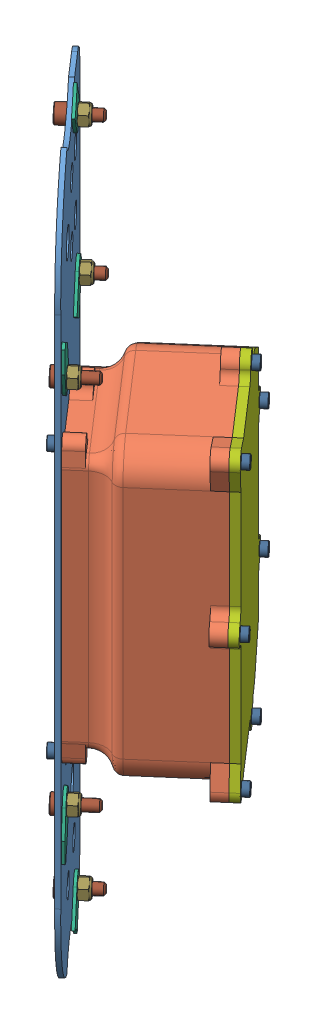
SolidWorks assembly EL-A0102-AA-Dashboard Assembly1, configuration Default. Lengths in mm.
Overall size (150 436.5 148.34).
102 component instances, 35 part files, 83 mates.
Components (placement in the parent):
- FR-40001-CF-Space Frame1-1: FR-40001-CF-Space Frame1 [Normal Chassis<As Machined>] at (-537.9548 -38.916 -519.6967) (suppressed, hidden)
- ST-A0200-AA-Inboard Steering1-1: ST-A0200-AA-Inboard Steering1 [Default] at (393.0306 -38.916 -479.6363) x (0 1 0) z (0 0 1) size (453.39 406.81 546.68) (suppressed, hidden)
  - ST-00020-AA-NARRco Rack MkII1-1: ST-00020-AA-NARRco Rack MkII1 [13t-Custom Length] at (0 -158.974 -60.8538) x (0 0 1) z (0 -1 0) size (60.02 415.44 50.74)
    - ST-00020-AA-NARRco Rack MkII Housing^ST-00020-AA-NARRco Rack MkII1-2: ST-00020-AA-NARRco Rack MkII Housing^ST-00020-AA-NARRco Rack MkII1 [17.4] at origin size (38.43 322.07 50.74) (virtual)
    - ST-00021-AA-NARRco Rack MkII Pinion^ST-00020-AA-NARRco Rack MkII1-1: ST-00021-AA-NARRco Rack MkII Pinion^ST-00020-AA-NARRco Rack MkII1 [Default] at (0 0 16.002) x (1 0 0) z (0 -1 0) size (58.43 56.52 31.98) (virtual)
    - ST-00022-AA-NARRco Rack MkII Rack^ST-00020-AA-NARRco Rack MkII1-1: ST-00022-AA-NARRco Rack MkII Rack^ST-00020-AA-NARRco Rack MkII1 [17.4] at origin size (15.88 404.88 15.88) (virtual)
    - ST-00023-AA-NARRco Rack MkII Bump Stop TT1119-01^ST-00020-AA-NARRco Rack MkII1-1: ST-00023-AA-NARRco Rack MkII Bump Stop TT1119-01^ST-00020-AA-NARRco Rack MkII1 [Default] at (0 194.818 0) x (-1 0 0) z (0 1 0) size (25.4 25.4 7.62) (virtual)
    - ST-00023-AA-NARRco Rack MkII Bump Stop TT1119-01^ST-00020-AA-NARRco Rack MkII1-2: ST-00023-AA-NARRco Rack MkII Bump Stop TT1119-01^ST-00020-AA-NARRco Rack MkII1 [Default] at (0 -194.818 0) x (1 0 0) z (0 -1 0) size (25.4 25.4 7.62) (virtual)
    - ST-10024-AA-Rack End Fastener^ST-00020-AA-NARRco Rack MkII1-1: ST-10024-AA-Rack End Fastener^ST-00020-AA-NARRco Rack MkII1 [Default] at (0 202.438 0) x (-0.837169 0 -0.546944) z (0 -1 0) size (12.7 12.7 31.32) (virtual)
    - ST-10024-AA-Rack End Fastener^ST-00020-AA-NARRco Rack MkII1-2: ST-10024-AA-Rack End Fastener^ST-00020-AA-NARRco Rack MkII1 [Default] at (0 -202.438 0) x (-0.837169 0 -0.546944) z (0 1 0) size (12.7 12.7 31.32) (virtual)
  - ST-00007-AA-SU Joint Borgeson1-1: ST-00007-AA-SU Joint Borgeson1 [Default] at (0 -174.976 36.3378) x (0 0.573576 0.819152) z (-1 0 0) size (87.37 64.05 41.39)
    - Clevis^ST-00007-AA-SU Joint Borgeson1-1: Clevis^ST-00007-AA-SU Joint Borgeson1 [Default] at (19.25 0 0) size (52.55 41.35 41.39) (virtual)
    - Clevis^ST-00007-AA-SU Joint Borgeson1-2: Clevis^ST-00007-AA-SU Joint Borgeson1 [Default] at (-15.7687 11.0413 0) x (-0.819152 0.573576 0) z (0.573576 0.819152 0) size (52.55 41.35 41.39) (virtual)
    - Joint^ST-00007-AA-SU Joint Borgeson1-1: Joint^ST-00007-AA-SU Joint Borgeson1 [Default] at origin size (15.41 40.1 40.1) (virtual)
  - ST-10008-AG-Lower Column1-1: ST-10008-AG-Lower Column1 [Single U-Joint] at (0 -176.646 33.9528) x (-0.165712 -0.807827 0.565646) z (0 0.573576 0.819152) size (30.03 24.96 239.93)
  - ST-00007-AB-SU Joint Borgeson1-1: ST-00007-AB-SU Joint Borgeson1 [Default] at (272.5838 -275.7567 2.1298) x (0 0.984808 -0.173648) z (0 0.173648 0.984808) size (106.79 41.39 97.86)
    - ST-00007-AA-SU Joint Borgeson1-1: ST-00007-AA-SU Joint Borgeson1 [Default] at (210.9791 272.5838 303.532) x (0.866025 0 0.5) z (0 1 0) size (87.37 64.05 41.39)
      - Clevis^ST-00007-AA-SU Joint Borgeson1-1: Clevis^ST-00007-AA-SU Joint Borgeson1 [Default] at (19.25 0 0) size (52.55 41.35 41.39) (virtual)
      - Clevis^ST-00007-AA-SU Joint Borgeson1-2: Clevis^ST-00007-AA-SU Joint Borgeson1 [Default] at (-15.7687 11.0413 0) x (-0.819152 0.573576 0) z (0.573576 0.819152 0) size (52.55 41.35 41.39) (virtual)
      - Joint^ST-00007-AA-SU Joint Borgeson1-1: Joint^ST-00007-AA-SU Joint Borgeson1 [Default] at origin size (15.41 40.1 40.1) (virtual)
  - ST-10004-AC-Upper Column1-1: ST-10004-AC-Upper Column1 [Default] at (0 -15.2751 264.4144) x (0 0.939693 0.34202) z (-0.909534 0.142154 -0.390564) size (101.6 19.05 19.05)
  - ST-10005-BB-Upper Support1-4: ST-10005-BB-Upper Support1 [Default] at (0 47.65 287.3172) x (-1 0 0) z (0 1 0) size (339.46 194.46 164.58)
  - ST-00006-AA-Upper Column Bearing (2938T23)1-1: ST-00006-AA-Upper Column Bearing (2938T23)1 [Default] at (0 23.7222 278.6082) x (0 0.939693 0.34202) z (-0.975708 -0.074928 0.205863) size (19.05 31.75 31.75)
  - ST-00006-AA-Upper Column Bearing (2938T23)1-2: ST-00006-AA-Upper Column Bearing (2938T23)1 [Default] at (0 71.5779 296.0263) x (0 -0.939693 -0.34202) z (0.727107 -0.234805 0.645121) size (19.05 31.75 31.75)
  - ST-00003-AA-Longacre Spud1-1: ST-00003-AA-Longacre Spud1 [Default] at (0 93.9543 304.1706) x (0 -0.939693 -0.34202) z (0.869392 -0.169 0.464323) size (53.97 27.38 27.32)
  - ST-#####-AA-MOMO MOD 121-1: ST-#####-AA-MOMO MOD 121 [Default] at (0 119.9927 313.6478) x (-0.999984 0.001925 -0.00529) z (0 0.939693 0.34202) size (250 198.03 35.56)
  - ST-00002-AA-Longacre Quick Disconnect_52-566051-1: ST-00002-AA-Longacre Quick Disconnect_52-566051 [Default] at (0 102.9646 307.4501) x (0 -0.939693 -0.34202) z (0.868826 0.16934 -0.465258) size (41.4 80.01 80.01)
  - ST-10009-AA-Lower Lower Column1-1: ST-10009-AA-Lower Lower Column1 [Single U-Joint] at (0 -174.976 -60.8538) x (0 1 0) z (0 0 1) size (30.03 24.96 55.78)
  - ST-10025-AA-Rack End Left1-1: ST-10025-AA-Rack End Left1 [Brute Forced Left] at (211.328 -158.974 -60.8538) x (0 0 -1) z (0 -1 0) size (25.4 30.73 21.27)
  - ST-10025-AA-Rack End1-1: ST-10025-AA-Rack End1 [Right] at (-211.328 -158.974 -60.8538) x (0 0 1) z (0 -1 0) size (25.4 30.73 21.27)
  - ST-00011-AB-Rack Mount Top1-1: ST-00011-AB-Rack Mount Top1 [Default] at (-155.4861 -158.974 -60.8538) x (0 1 0) z (0 0 1) size (59.69 11.13 15.88)
  - ST-00011-AB-Rack Mount Top1-2: ST-00011-AB-Rack Mount Top1 [Default] at (155.4861 -158.974 -60.8538) x (0 1 0) z (0 0 1) size (59.69 11.13 15.88)
  - ST-00012-AB-Rack Mount Bottom1-1: ST-00012-AB-Rack Mount Bottom1 [Default] at (-155.4861 -158.974 -60.8538) x (0 1 0) z (0 0 1) size (59.69 11.13 15.88)
  - ST-00012-AB-Rack Mount Bottom1-2: ST-00012-AB-Rack Mount Bottom1 [Default] at (155.4861 -158.974 -60.8538) x (0 1 0) z (0 0 1) size (59.69 11.13 15.88)
  - ST-70001-AB-Steering Rack Cover1-1: ST-70001-AB-Steering Rack Cover1 [Default] at (161.925 -244.8955 -31.75) x (-1 0 0) z (0 0 -1) size (388.4 152.4 55.88)
- EL-70040-AA-Dashboard Carbon Fiber Panel1-1: EL-70040-AA-Dashboard Carbon Fiber Panel1 [Default] at (408.7648 -38.916 -97.5804) x (0 1 0) z (0.656059 0 0.75471) size (431.8 2.54 114.47)
- EL-50041-AA-Dashboard Enclosure1-1: EL-50041-AA-Dashboard Enclosure1 [Default] at (434.2682 -38.916 -85.6643) x (0 1 0) z (-0.75471 0 0.656059) size (193.57 128.03 71.31)
- EL-80042-AA-Dashboard Display1-1: EL-80042-AA-Dashboard Display1 [Default] at (371.1883 85.036 -159.3307) x (0 -1 0) z (-0.75471 0 0.656059) size (132.58 114.23 10.91)
- EL-80043-AA-Dashboard PCB1-1: EL-80043-AA-Dashboard PCB1 [Default] at (483.1498 42.917 -55.7696) x (0 -1 0) z (0.75471 0 -0.656059) size (155.1 102.36 35.96)
- EL-80044-AA-Dashboard Controller Board1-1: EL-80044-AA-Dashboard Controller Board1 [Default] at (444.9269 -38.916 -86.7478) x (0 1 0) z (0.656059 0 0.75471) size (105.53 3.5 40.03)
- EL-30045-AA-Carbon Fiber Dash Panel Tabs1-1: EL-30045-AA-Carbon Fiber Dash Panel Tabs1 [Default] at (398.9627 -147.7409 -108.8565) x (0.525497 -0.598678 0.604515) z (0.75471 0 -0.656059) size (15.88 26.99 1.59)
- EL-30045-AA-Carbon Fiber Dash Panel Tabs1-2: EL-30045-AA-Carbon Fiber Dash Panel Tabs1 [Round Cutout] at (408.0839 -237.4011 -100.7835) x (0.5205 0.608735 0.598767) z (-0.75471 0 0.656059) size (15.88 26.76 1.59)
- EL-30045-AA-Carbon Fiber Dash Panel Tabs1-3: EL-30045-AA-Carbon Fiber Dash Panel Tabs1 [Middle Tabs] at (450.7883 -148.5331 -51.6576) x (0.603667 0.391586 0.69444) z (-0.75471 0 0.656059) size (15.88 33.34 1.59)
- EL-30045-AA-Carbon Fiber Dash Panel Tabs1-4: EL-30045-AA-Carbon Fiber Dash Panel Tabs1 [Default] at (400.1608 69.9089 -109.898) x (0.525497 0.598678 0.604515) z (-0.75471 0 0.656059) size (15.88 26.99 1.59)
- EL-30045-AA-Carbon Fiber Dash Panel Tabs1-5: EL-30045-AA-Carbon Fiber Dash Panel Tabs1 [Middle Tabs] at (449.5902 70.7011 -50.6161) x (0.603667 -0.391586 0.69444) z (0.75471 0 -0.656059) size (15.88 33.34 1.59)
- EL-30045-AA-Carbon Fiber Dash Panel Tabs1-6: EL-30045-AA-Carbon Fiber Dash Panel Tabs1 [Round Cutout] at (406.8858 159.5691 -99.742) x (0.5205 -0.608735 0.598767) z (0.75471 0 -0.656059) size (15.88 26.76 1.59)
- EL-60046-AA-Dashboard Enclosure Lid1-2: EL-60046-AA-Dashboard Enclosure Lid1 [Default] at (512.3994 -125.4743 -87.057) x (0.656059 0 0.75471) z (-0.75471 0 0.656059) size (128.03 193.57 4.76)
- EL-60047-AA-Dashboard Panel Clear Screen1-1: EL-60047-AA-Dashboard Panel Clear Screen1 [Default] at (431.2611 -38.916 -71.7014) x (0.75471 0 -0.656059) z (0 -1 0) size (1.59 66.67 114.3)
- AC-Heat Set Insert, M4x7-4.7 (94180A351)1-1: AC-Heat Set Insert, M4x7-4.7 (94180A351)1 [94180A351] at (393.689 -77.047 -118.5052) x (0.656059 0 0.75471) z (-0.75471 0 0.656059) size (6.35 6.35 4.7)
- AC-Heat Set Insert, M4x7-4.7 (94180A351)1-2: AC-Heat Set Insert, M4x7-4.7 (94180A351)1 [94180A351] at (423.6661 -117.916 -84.0204) x (0.544178 -0.558559 0.626005) z (-0.75471 0 0.656059) size (6.35 6.35 4.7)
- AC-Heat Set Insert, M4x7-4.7 (94180A351)1-3: AC-Heat Set Insert, M4x7-4.7 (94180A351)1 [94180A351] at (454.7239 -117.6987 -48.2925) x (0.544178 -0.558559 0.626005) z (-0.75471 0 0.656059) size (6.35 6.35 4.7)
- BR-Black Oxide C12.9 SHCS, M4x0.7-8 (91290A140)1-1: BR-Black Oxide C12.9 SHCS, M4x0.7-8 (91290A140)1 [91290A140] at (391.5079 -77.047 -116.6092) x (0.656059 0 0.75471) z (-0.75471 0 0.656059) size (7 7 12.17)
- BR-Black Oxide C12.9 SHCS, M4x0.7-8 (91290A140)1-2: BR-Black Oxide C12.9 SHCS, M4x0.7-8 (91290A140)1 [91290A140] at (421.485 -117.916 -82.1244) x (0.656059 0 0.75471) z (-0.75471 0 0.656059) size (7 7 12.17)
- BR-Black Oxide C12.9 SHCS, M4x0.7-8 (91290A140)1-3: BR-Black Oxide C12.9 SHCS, M4x0.7-8 (91290A140)1 [91290A140] at (452.5428 -117.6987 -46.3965) x (0.656059 0 0.75471) z (-0.75471 0 0.656059) size (7 7 12.17)
- FS-Black Oxide C12.9 SHCS, M6x1-16 (91290A321)1-1: FS-Black Oxide C12.9 SHCS, M6x1-16 (91290A321)1 [91290A321] at (453.6086 -148.5331 -54.1093) x (0.167998 -0.966658 0.19326) z (-0.75471 0 0.656059) size (10 10 22.29)
- EL-Steel Nylon Locknut, C8, M6x1-6 (90576A115)1-1: EL-Steel Nylon Locknut, C8, M6x1-6 (90576A115)1 [90576A115] at (453.0524 -148.5331 -53.6258) x (-0.656059 0 -0.75471) z (0.75471 0 -0.656059) size (10 11.55 6)
- FS-Black Oxide C12.9 SHCS, M6x1-16 (91290A321)1-2: FS-Black Oxide C12.9 SHCS, M6x1-16 (91290A321)1 [91290A321] at (400.8193 -147.7409 -110.4704) x (0.167998 -0.966658 0.19326) z (-0.75471 0 0.656059) size (10 10 22.29)
- FS-Black Oxide C12.9 SHCS, M6x1-16 (91290A321)1-3: FS-Black Oxide C12.9 SHCS, M6x1-16 (91290A321)1 [91290A321] at (408.7424 -237.4011 -101.3559) x (0.185994 -0.958972 0.213962) z (-0.75471 0 0.656059) size (10 10 22.29)
- EL-Steel Nylon Locknut, C8, M6x1-6 (90576A115)1-2: EL-Steel Nylon Locknut, C8, M6x1-6 (90576A115)1 [90576A115] at (410.348 -237.4011 -102.7516) x (-0.656059 0 -0.75471) z (0.75471 0 -0.656059) size (10 11.55 6)
- EL-Steel Nylon Locknut, C8, M6x1-6 (90576A115)1-3: EL-Steel Nylon Locknut, C8, M6x1-6 (90576A115)1 [90576A115] at (402.4249 -147.7409 -111.8661) x (-0.653043 -0.095776 -0.75124) z (0.75471 0 -0.656059) size (10 11.55 6)
- BR-Black Oxide C12.9 SHCS, M4x0.7-8 (91290A140)1-4: BR-Black Oxide C12.9 SHCS, M4x0.7-8 (91290A140)1 [91290A140] at (426.346 -100.006 -100.0441) x (0.387749 -0.806652 0.446054) z (-0.75471 0 0.656059) size (7 7 12.17)
- AC-Heat Set Insert, M4x7-4.7 (94180A351)1-4: AC-Heat Set Insert, M4x7-4.7 (94180A351)1 [94180A351] at (427.5158 -100.006 -101.061) x (0.544178 -0.558559 0.626005) z (-0.75471 0 0.656059) size (6.35 6.35 4.7)
- AC-Heat Set Insert, M4x7-4.7 (94180A351)1-5: AC-Heat Set Insert, M4x7-4.7 (94180A351)1 [94180A351] at (456.6776 -100.006 -67.5141) x (0.544178 -0.558559 0.626005) z (-0.75471 0 0.656059) size (6.35 6.35 4.7)
- BR-Black Oxide C12.9 SHCS, M4x0.7-8 (91290A140)1-5: BR-Black Oxide C12.9 SHCS, M4x0.7-8 (91290A140)1 [91290A140] at (455.5078 -100.006 -66.4972) x (0.646596 -0.169233 0.743824) z (-0.75471 0 0.656059) size (7 7 12.17)
- AC-Heat Set Insert, M2x0.4-2.9(94180A307)-1: AC-Heat Set Insert, M2x0.4-2.9(94180A307) [94180A307] at (431.5138 -89.166 -98.2757) x (-0.423191 0.764141 -0.486825) z (0.75471 0 -0.656059) size (3.58 3.58 2.92)
- AC-Heat Set Insert, M2x0.4-2.9(94180A307)-2: AC-Heat Set Insert, M2x0.4-2.9(94180A307) [94180A307] at (454.4758 -89.166 -71.8608) x (-0.423191 0.764141 -0.486825) z (0.75471 0 -0.656059) size (3.58 3.58 2.92)
- 90128A177_Zinc-Plated Alloy Steel Socket Head Screw, M2x0.4, 5mm1-1: 90128A177_Zinc-Plated Alloy Steel Socket Head Screw, M2x0.4, 5mm1 [90128A177] at (432.3141 -89.166 -98.9714) x (-0.618493 -0.333528 -0.711495) z (0.75471 0 -0.656059) size (3.8 3.8 7.09)
- 90128A177_Zinc-Plated Alloy Steel Socket Head Screw, M2x0.4, 5mm1-2: 90128A177_Zinc-Plated Alloy Steel Socket Head Screw, M2x0.4, 5mm1 [90128A177] at (455.2762 -89.166 -72.5566) x (0.466551 0.703049 0.536705) z (0.75471 0 -0.656059) size (3.8 3.8 7.09)
- AC-Heat Set Insert, M4x7-4.7 (94180A351)1-6: AC-Heat Set Insert, M4x7-4.7 (94180A351)1 [94180A351] at (473.7243 -129.6987 -127.9655) x (0.032788 0.99875 0.037718) z (0.75471 0 -0.656059) size (6.35 6.35 4.7)
- BR-Black Oxide C12.9 SHCS, M4x0.7-8 (91290A140)1-6: BR-Black Oxide C12.9 SHCS, M4x0.7-8 (91290A140)1 [91290A140] at (518.6227 -122.8067 -84.1086) x (0.649068 -0.145601 0.746667) z (0.75471 0 -0.656059) size (7 7 12.17)
- AC-Heat Set Insert, M4x7-4.7 (94180A351)1-7: AC-Heat Set Insert, M4x7-4.7 (94180A351)1 [94180A351] at (442.8335 -76.9989 -163.5013) x (-0.331829 0.862655 -0.381726) z (0.75471 0 -0.656059) size (6.35 6.35 4.7)
- AC-Heat Set Insert, M4x7-4.7 (94180A351)1-8: AC-Heat Set Insert, M4x7-4.7 (94180A351)1 [94180A351] at (514.7643 -122.8067 -80.7545) x (-0.582666 0.459592 -0.67028) z (0.75471 0 -0.656059) size (6.35 6.35 4.7)
- AC-Heat Set Insert, M4x7-4.7 (94180A351)1-9: AC-Heat Set Insert, M4x7-4.7 (94180A351)1 [94180A351] at (518.9578 -38.916 -75.9303) x (-0.363579 0.832393 -0.418249) z (0.75471 0 -0.656059) size (6.35 6.35 4.7)
- BR-Black Oxide C12.9 SHCS, M4x0.7-8 (91290A140)1-7: BR-Black Oxide C12.9 SHCS, M4x0.7-8 (91290A140)1 [91290A140] at (477.5828 -129.6987 -131.3196) x (0.573981 -0.484318 0.660289) z (0.75471 0 -0.656059) size (7 7 12.17)
- BR-Black Oxide C12.9 SHCS, M4x0.7-8 (91290A140)1-8: BR-Black Oxide C12.9 SHCS, M4x0.7-8 (91290A140)1 [91290A140] at (446.692 -76.9989 -166.8554) x (0.573981 -0.484318 0.660289) z (0.75471 0 -0.656059) size (7 7 12.17)
- BR-Black Oxide C12.9 SHCS, M4x0.7-8 (91290A140)1-9: BR-Black Oxide C12.9 SHCS, M4x0.7-8 (91290A140)1 [91290A140] at (522.8163 -38.916 -79.2844) x (0.649068 -0.145601 0.746667) z (0.75471 0 -0.656059) size (7 7 12.17)
- AC-Heat Set Insert, M4x7-4.7 (94180A351)1-10: AC-Heat Set Insert, M4x7-4.7 (94180A351)1 [94180A351] at (393.689 -0.785 -118.5052) x (0.656059 0 0.75471) z (0.75471 0 -0.656059) size (6.35 6.35 4.7)
- BR-Black Oxide C12.9 SHCS, M4x0.7-8 (91290A140)1-10: BR-Black Oxide C12.9 SHCS, M4x0.7-8 (91290A140)1 [91290A140] at (391.5079 -0.785 -116.6092) x (-0.656059 0 -0.75471) z (-0.75471 0 0.656059) size (7 7 12.17)
- AC-Heat Set Insert, M4x7-4.7 (94180A351)1-11: AC-Heat Set Insert, M4x7-4.7 (94180A351)1 [94180A351] at (423.6661 40.084 -84.0204) x (0.544178 0.558559 0.626005) z (-0.75471 0 0.656059) size (6.35 6.35 4.7)
- BR-Black Oxide C12.9 SHCS, M4x0.7-8 (91290A140)1-11: BR-Black Oxide C12.9 SHCS, M4x0.7-8 (91290A140)1 [91290A140] at (421.485 40.084 -82.1244) x (-0.656059 0 -0.75471) z (-0.75471 0 0.656059) size (7 7 12.17)
- AC-Heat Set Insert, M4x7-4.7 (94180A351)1-12: AC-Heat Set Insert, M4x7-4.7 (94180A351)1 [94180A351] at (454.7239 39.8667 -48.2925) x (0.544178 0.558559 0.626005) z (-0.75471 0 0.656059) size (6.35 6.35 4.7)
- BR-Black Oxide C12.9 SHCS, M4x0.7-8 (91290A140)1-12: BR-Black Oxide C12.9 SHCS, M4x0.7-8 (91290A140)1 [91290A140] at (452.5428 39.8667 -46.3965) x (-0.656059 0 -0.75471) z (-0.75471 0 0.656059) size (7 7 12.17)
- AC-Heat Set Insert, M4x7-4.7 (94180A351)1-13: AC-Heat Set Insert, M4x7-4.7 (94180A351)1 [94180A351] at (456.6776 22.174 -67.5141) x (0.544178 0.558559 0.626005) z (-0.75471 0 0.656059) size (6.35 6.35 4.7)
- BR-Black Oxide C12.9 SHCS, M4x0.7-8 (91290A140)1-13: BR-Black Oxide C12.9 SHCS, M4x0.7-8 (91290A140)1 [91290A140] at (455.5078 22.174 -66.4972) x (-0.646596 -0.169233 -0.743824) z (-0.75471 0 0.656059) size (7 7 12.17)
- BR-Black Oxide C12.9 SHCS, M4x0.7-8 (91290A140)1-14: BR-Black Oxide C12.9 SHCS, M4x0.7-8 (91290A140)1 [91290A140] at (426.346 22.174 -100.0441) x (-0.387749 -0.806652 -0.446054) z (-0.75471 0 0.656059) size (7 7 12.17)
- AC-Heat Set Insert, M4x7-4.7 (94180A351)1-14: AC-Heat Set Insert, M4x7-4.7 (94180A351)1 [94180A351] at (427.5158 22.174 -101.061) x (0.544178 0.558559 0.626005) z (-0.75471 0 0.656059) size (6.35 6.35 4.7)
- 90128A177_Zinc-Plated Alloy Steel Socket Head Screw, M2x0.4, 5mm1-3: 90128A177_Zinc-Plated Alloy Steel Socket Head Screw, M2x0.4, 5mm1 [90128A177] at (432.3141 11.334 -98.9714) x (0.618493 -0.333528 0.711495) z (0.75471 0 -0.656059) size (3.8 3.8 7.09)
- 90128A177_Zinc-Plated Alloy Steel Socket Head Screw, M2x0.4, 5mm1-4: 90128A177_Zinc-Plated Alloy Steel Socket Head Screw, M2x0.4, 5mm1 [90128A177] at (455.2762 11.334 -72.5566) x (-0.466551 0.703049 -0.536705) z (0.75471 0 -0.656059) size (3.8 3.8 7.09)
- FS-Black Oxide C12.9 SHCS, M6x1-16 (91290A321)1-4: FS-Black Oxide C12.9 SHCS, M6x1-16 (91290A321)1 [91290A321] at (453.6086 70.7011 -54.1093) x (-0.167998 -0.966658 -0.19326) z (-0.75471 0 0.656059) size (10 10 22.29)
- EL-Steel Nylon Locknut, C8, M6x1-6 (90576A115)1-4: EL-Steel Nylon Locknut, C8, M6x1-6 (90576A115)1 [90576A115] at (453.0524 70.7011 -53.6258) x (-0.656059 0 -0.75471) z (0.75471 0 -0.656059) size (10 11.55 6)
- EL-Steel Nylon Locknut, C8, M6x1-6 (90576A115)1-5: EL-Steel Nylon Locknut, C8, M6x1-6 (90576A115)1 [90576A115] at (402.4249 69.9089 -111.8661) x (-0.653043 0.095776 -0.75124) z (0.75471 0 -0.656059) size (10 11.55 6)
- FS-Black Oxide C12.9 SHCS, M6x1-16 (91290A321)1-5: FS-Black Oxide C12.9 SHCS, M6x1-16 (91290A321)1 [91290A321] at (400.8193 69.9089 -110.4704) x (-0.167998 -0.966658 -0.19326) z (-0.75471 0 0.656059) size (10 10 22.29)
- FS-Black Oxide C12.9 SHCS, M6x1-16 (91290A321)1-6: FS-Black Oxide C12.9 SHCS, M6x1-16 (91290A321)1 [91290A321] at (408.7424 159.5691 -101.3559) x (-0.185994 -0.958972 -0.213962) z (-0.75471 0 0.656059) size (10 10 22.29)
- EL-Steel Nylon Locknut, C8, M6x1-6 (90576A115)1-6: EL-Steel Nylon Locknut, C8, M6x1-6 (90576A115)1 [90576A115] at (410.348 159.5691 -102.7516) x (-0.656059 0 -0.75471) z (0.75471 0 -0.656059) size (10 11.55 6)
- AC-Heat Set Insert, M4x7-4.7 (94180A351)1-15: AC-Heat Set Insert, M4x7-4.7 (94180A351)1 [94180A351] at (514.7643 44.9747 -80.7545) x (0.582666 0.459592 0.67028) z (0.75471 0 -0.656059) size (6.35 6.35 4.7)
- BR-Black Oxide C12.9 SHCS, M4x0.7-8 (91290A140)1-15: BR-Black Oxide C12.9 SHCS, M4x0.7-8 (91290A140)1 [91290A140] at (518.6227 44.9747 -84.1086) x (-0.649068 -0.145601 -0.746667) z (0.75471 0 -0.656059) size (7 7 12.17)
- BR-Black Oxide C12.9 SHCS, M4x0.7-8 (91290A140)1-16: BR-Black Oxide C12.9 SHCS, M4x0.7-8 (91290A140)1 [91290A140] at (477.5828 51.8667 -131.3196) x (-0.573981 -0.484318 -0.660289) z (0.75471 0 -0.656059) size (7 7 12.17)
- AC-Heat Set Insert, M4x7-4.7 (94180A351)1-16: AC-Heat Set Insert, M4x7-4.7 (94180A351)1 [94180A351] at (473.7243 51.8667 -127.9655) x (-0.032788 0.99875 -0.037718) z (0.75471 0 -0.656059) size (6.35 6.35 4.7)
- AC-Heat Set Insert, M4x7-4.7 (94180A351)1-17: AC-Heat Set Insert, M4x7-4.7 (94180A351)1 [94180A351] at (442.8335 -0.8331 -163.5013) x (0.331829 0.862655 0.381726) z (0.75471 0 -0.656059) size (6.35 6.35 4.7)
- BR-Black Oxide C12.9 SHCS, M4x0.7-8 (91290A140)1-17: BR-Black Oxide C12.9 SHCS, M4x0.7-8 (91290A140)1 [91290A140] at (446.692 -0.8331 -166.8554) x (-0.573981 -0.484318 -0.660289) z (0.75471 0 -0.656059) size (7 7 12.17)
- AC-Heat Set Insert, M2x0.4-2.9(94180A307)-3: AC-Heat Set Insert, M2x0.4-2.9(94180A307) [94180A307] at (454.4758 11.334 -71.8608) x (0.423191 0.764141 0.486825) z (0.75471 0 -0.656059) size (3.58 3.58 2.92)
- AC-Heat Set Insert, M2x0.4-2.9(94180A307)-4: AC-Heat Set Insert, M2x0.4-2.9(94180A307) [94180A307] at (431.5138 11.334 -98.2757) x (0.423191 0.764141 0.486825) z (0.75471 0 -0.656059) size (3.58 3.58 2.92)
Mates (geometry in assembly coordinates):
- Coincident5: coincident: cylinder of ST-A0200-AA-Inboard Steering1-1/ST-10005-BB-Upper Support1-4; unknown of FR-40001-CF-Space Frame1-1
- Parallel2: parallel aligned: plane of ST-A0200-AA-Inboard Steering-1 through (393.0306 -38.916 -479.6363) normal (0 1 0)
- Parallel4: parallel aligned: plane of ST-A0200-AA-Inboard Steering-1 through (393.0306 -38.916 -479.6363) normal (0 0 1)
- Tangent2: tangent anti-aligned: cylinder of ST-A0200-AA-Inboard Steering-1/ST-10005-BB-Upper Support-4 through (339.0305 -43.996 -192.319) axis (0.537412 -0.573576 0.618222) radius 9.525; plane of Carbon Fiber Dashboard Panel-1 through (421.3036 117.9839 -83.1562) normal (0.75471 0 -0.656059)
- Tangent3: tangent anti-aligned: cylinder of ST-A0200-AA-Inboard Steering-1/ST-10005-BB-Upper Support-4 through (468.7081 104.568 -43.1421) axis (-0.537412 -0.573576 -0.618222) radius 9.525; plane of Carbon Fiber Dashboard Panel-1 through (421.3036 117.9839 -83.1562) normal (0.75471 0 -0.656059)
- Coincident10: coincident aligned: plane of FR-40001-CF-Space Frame-1 through (-537.9548 -38.916 -519.6967) normal (0 1 0); plane of EL-70040-AA-Dashboard Carbon Fiber Panel-1 through (408.7648 -38.916 -97.5804) normal (0 1 0)
- Tangent5: tangent anti-aligned: torus of ST-A0200-AA-Inboard Steering-1/ST-10005-BB-Upper Support-4; plane of Carbon Fiber Dashboard Panel-1 through (458.0942 113.484 -36.9618) normal (0.656059 0 0.75471)
- Coincident11: coincident anti-aligned: plane of Carbon Fiber Dashboard Panel-1 through (421.3036 117.9839 -83.1562) normal (0.75471 0 -0.656059); plane of BA-Dashboard Enclosure-1 through (425.6419 -38.916 -78.1655) normal (-0.75471 0 0.656059)
- Coincident14: coincident aligned: plane of FR-40001-CF-Space Frame-1 through (-537.9548 -38.916 -519.6967) normal (0 1 0); plane of BA-Dashboard Enclosure-1 through (434.2682 -38.916 -85.6643) normal (0 1 0)
- Distance1: distance = 3.175 mm anti-aligned: plane of Dashboard Display-1 through (455.0146 -93.776 -49.2156) normal (-0.75471 0 0.656059); plane of Carbon Fiber Dashboard Panel-1 through (421.3036 117.9839 -83.1562) normal (0.75471 0 -0.656059)
- Width1: width anti-aligned: plane of Carbon Fiber Dashboard Panel-1 through (451.2577 15.059 -48.6979) normal (0 -1 0); plane of Carbon Fiber Dashboard Panel-1 through (451.2577 -92.891 -48.6979) normal (0 1 0); plane of Dashboard Display-1 through (422.4619 27.374 -103.2928) normal (0 1 0); plane of Dashboard Display-1 through (422.4619 -105.206 -103.2928) normal (0 -1 0)
- Distance2: distance = 4.7625 mm aligned: plane of BA-Dashboard Enclosure-1 through (456.8867 -38.916 -42.2225) normal (0.656059 0 0.75471); plane of Carbon Fiber Dashboard Panel-1 through (458.0942 113.484 -36.9618) normal (0.656059 0 0.75471)
- Distance3: distance = 1.5 mm anti-aligned: plane of Dashboard Display-1 through (457.2449 -38.916 -51.1465) normal (0.656059 0 0.75471); plane of BA-Dashboard Enclosure-1 through (453.6064 -38.916 -45.996) normal (-0.656059 0 -0.75471)
- Distance4: distance = 8 mm anti-aligned: plane of NHD-4.3-480272MF-34-Controller-Board-1 through (444.8514 -38.916 -86.6822) normal (0.75471 0 -0.656059); plane of Dashboard PCB-1 through (448.7235 -39.6458 -94.4219) normal (-0.75471 0 0.656059)
- Concentric1: concentric aligned: cylinder of Dashboard Display-1 through (452.1133 -81.416 -63.5464) axis (0.75471 0 -0.656059) radius 1.2245; circle of Dashboard PCB-1
- Parallel6: parallel anti-aligned: plane of BA-Dashboard Enclosure-1 through (453.6064 -38.916 -45.996) normal (-0.656059 0 -0.75471); plane of Dashboard PCB-1 through (472.9084 -115.846 -66.6003) normal (0.656059 0 0.75471)
- Distance5: distance = 5 mm anti-aligned: plane of NHD-4.3-480272MF-34-Controller-Board-1 through (444.0967 -38.916 -86.0261) normal (-0.75471 0 0.656059); plane of Dashboard Display-1 through (422.4619 -103.206 -103.2928) normal (0.75471 0 -0.656059)
- Symmetric1: symmetric aligned: plane of Dashboard Display-1 through (411.3864 -38.916 -103.9007) normal (-0.656059 0 -0.75471); plane of NHD-4.3-480272MF-34-Controller-Board-1 through (457.2449 -38.916 -51.1465) normal (0.656059 0 0.75471); plane of Dashboard Display-1 through (444.9269 -38.916 -86.7478) normal (0.656059 0 0.75471)
- Coincident18: coincident aligned: plane of BA-Dashboard Enclosure-1 through (434.2682 -38.916 -85.6643) normal (0 1 0); plane of NHD-4.3-480272MF-34-Controller-Board-1 through (444.9269 -38.916 -86.7478) normal (0 1 0)
- Coincident19: coincident anti-aligned: plane of BA-Dashboard Enclosure-1 through (442.4153 -38.916 -92.7465) normal (0.75471 0 -0.656059); plane of Dashboard Enclosure Lid-1
- Coincident20: coincident anti-aligned: plane of BA-Dashboard Enclosure-1 through (425.6419 -113.916 -78.1655) normal (0 -1 0); plane of Dashboard Enclosure Lid-1 through (505.9428 -118.291 -84.8663) normal (0 1 0)
- Coincident21: coincident aligned: plane of BA-Dashboard Enclosure-1 through (456.8867 -38.916 -42.2225) normal (0.656059 0 0.75471); plane of Dashboard Enclosure Lid-1 through (505.9428 -118.291 -84.8663) normal (0.656059 0 0.75471)
- Coincident22: coincident anti-aligned: plane of Carbon Fiber Dashboard Panel-1 through (421.3036 117.9839 -83.1562) normal (0.75471 0 -0.656059); plane of EL-30045-AA-Carbon Fiber Dash Panel Tabs-1 through (398.9627 -147.7409 -108.8565) normal (-0.75471 0 0.656059)
- Coincident231: coincident anti-aligned: plane of Carbon Fiber Dashboard Panel-1 through (421.3036 117.9839 -83.1562) normal (0.75471 0 -0.656059); plane of EL-30045-AA-Carbon Fiber Dash Panel Tabs-2 through (406.8858 -237.4011 -99.742) normal (-0.75471 0 0.656059)
- Coincident241: coincident anti-aligned: plane of Carbon Fiber Dashboard Panel-1 through (421.3036 117.9839 -83.1562) normal (0.75471 0 -0.656059); plane of EL-30045-AA-Carbon Fiber Dash Panel Tabs-3 through (449.5902 -148.5331 -50.6161) normal (-0.75471 0 0.656059)
- Coincident242: coincident anti-aligned: plane of BA-Dashboard Enclosure-1 through (479.4602 -38.916 -124.9491) normal (0.75471 0 -0.656059); plane of Dashboard Enclosure Lid-2
- Concentric2: concentric aligned: cylinder of BA-Dashboard Enclosure-1 through (397.9531 -77.047 -122.2119) axis (-0.75471 0 0.656059) radius 3.025; cylinder of AC-Heat Set Insert, M4x7-4.7 (94180A351)-1 through (391.9154 -77.047 -116.9634) axis (-0.75471 0 0.656059) radius 2
- Coincident243: coincident aligned: plane of BA-Dashboard Enclosure-1 through (425.6419 -38.916 -78.1655) normal (-0.75471 0 0.656059); plane of AC-Heat Set Insert, M4x7-4.7 (94180A351)-1 through (391.9154 -75.047 -116.9634) normal (-0.75471 0 0.656059)
- Concentric31: concentric aligned: cylinder of BA-Dashboard Enclosure-1 through (427.9302 -117.916 -87.7272) axis (-0.75471 0 0.656059) radius 3.025; cylinder of AC-Heat Set Insert, M4x7-4.7 (94180A351)-2 through (421.8925 -117.916 -82.4787) axis (-0.75471 0 0.656059) radius 2
- Coincident244: coincident aligned: plane of BA-Dashboard Enclosure-1 through (425.6419 -38.916 -78.1655) normal (-0.75471 0 0.656059); plane of AC-Heat Set Insert, M4x7-4.7 (94180A351)-2 through (422.6254 -116.2571 -81.6356) normal (-0.75471 0 0.656059)
- Concentric41: concentric aligned: cylinder of BA-Dashboard Enclosure-1 through (458.988 -117.6987 -51.9992) axis (-0.75471 0 0.656059) radius 3.025; cylinder of AC-Heat Set Insert, M4x7-4.7 (94180A351)-3 through (452.9503 -117.6987 -46.7508) axis (-0.75471 0 0.656059) radius 2
- Coincident245: coincident aligned: plane of BA-Dashboard Enclosure-1 through (425.6419 -38.916 -78.1655) normal (-0.75471 0 0.656059); plane of AC-Heat Set Insert, M4x7-4.7 (94180A351)-3 through (453.6832 -116.0398 -45.9077) normal (-0.75471 0 0.656059)
- Concentric5: concentric anti-aligned: cylinder of AC-Heat Set Insert, M4x7-4.7 (94180A351)-1 through (391.9154 -77.047 -116.9634) axis (-0.75471 0 0.656059) radius 2; cylinder of BR-Black Oxide C12.9 SHCS, M4x0.7-8 (91290A140)-1 through (396.0361 -77.047 -120.5455) axis (0.75471 0 -0.656059) radius 2
- Coincident246: coincident: line of Carbon Fiber Dashboard Panel-1 through (383.1067 164.284 -123.2251) axis (0 -1 0); plane of BR-Black Oxide C12.9 SHCS, M4x0.7-8 (91290A140)-1 through (389.9984 -73.747 -115.297) normal (0.75471 0 -0.656059)
- Concentric6: concentric anti-aligned: cylinder of AC-Heat Set Insert, M4x7-4.7 (94180A351)-2 through (421.8925 -117.916 -82.4787) axis (-0.75471 0 0.656059) radius 2; cylinder of BR-Black Oxide C12.9 SHCS, M4x0.7-8 (91290A140)-2 through (426.0132 -117.916 -86.0608) axis (0.75471 0 -0.656059) radius 2
- Coincident247: coincident anti-aligned: plane of Carbon Fiber Dashboard Panel-1 through (419.3866 117.9839 -81.4898) normal (-0.75471 0 0.656059); plane of BR-Black Oxide C12.9 SHCS, M4x0.7-8 (91290A140)-2 through (419.9755 -114.616 -80.8123) normal (0.75471 0 -0.656059)
- Concentric7: concentric anti-aligned: cylinder of AC-Heat Set Insert, M4x7-4.7 (94180A351)-3 through (452.9503 -117.6987 -46.7508) axis (-0.75471 0 0.656059) radius 2; cylinder of BR-Black Oxide C12.9 SHCS, M4x0.7-8 (91290A140)-3 through (457.0711 -117.6987 -50.3328) axis (0.75471 0 -0.656059) radius 2
- Coincident248: coincident anti-aligned: plane of Carbon Fiber Dashboard Panel-1 through (419.3866 117.9839 -81.4898) normal (-0.75471 0 0.656059); plane of BR-Black Oxide C12.9 SHCS, M4x0.7-8 (91290A140)-3 through (451.0334 -114.3987 -45.0844) normal (0.75471 0 -0.656059)
- Concentric9: concentric anti-aligned: cylinder of FS-Black Oxide C12.9 SHCS, M6x1-16 (91290A321)-1 through (461.9104 -148.5331 -61.3259) axis (0.75471 0 -0.656059) radius 3; cylinder of EL-Steel Nylon Locknut, C8, M6x1-6 (90576A115)-1 through (455.3166 -148.5331 -55.594) axis (-0.75471 0 0.656059) radius 3
- Coincident249: coincident anti-aligned: plane of EL-30045-AA-Carbon Fiber Dash Panel Tabs-3 through (450.7883 -148.5331 -51.6576) normal (0.75471 0 -0.656059); plane of EL-Steel Nylon Locknut, C8, M6x1-6 (90576A115)-1 through (450.7883 -148.5331 -51.6576) normal (-0.75471 0 0.656059)
- Concentric10: concentric aligned: cylinder of EL-30045-AA-Carbon Fiber Dash Panel Tabs-1 through (400.1608 -147.7409 -109.898) axis (0.75471 0 -0.656059) radius 3.3; cylinder of FS-Black Oxide C12.9 SHCS, M6x1-16 (91290A321)-2 through (409.1211 -147.7409 -117.687) axis (0.75471 0 -0.656059) radius 3
- Coincident250: coincident anti-aligned: plane of Carbon Fiber Dashboard Panel-1 through (419.3866 117.9839 -81.4898) normal (-0.75471 0 0.656059); plane of FS-Black Oxide C12.9 SHCS, M6x1-16 (91290A321)-2 through (400.0264 -146.5373 -103.7612) normal (0.75471 0 -0.656059)
- Concentric11: concentric anti-aligned: circle of Carbon Fiber Dash Panel Tabs-2; cylinder of FS-Black Oxide C12.9 SHCS, M6x1-16 (91290A321)-3 through (417.0442 -237.4011 -108.5725) axis (0.75471 0 -0.656059) radius 3
- Coincident251: coincident anti-aligned: plane of Carbon Fiber Dashboard Panel-1 through (419.3866 117.9839 -81.4898) normal (-0.75471 0 0.656059); plane of FS-Black Oxide C12.9 SHCS, M6x1-16 (91290A321)-3 through (407.9258 -236.0687 -94.674) normal (0.75471 0 -0.656059)
- Concentric12: concentric anti-aligned: cylinder of FS-Black Oxide C12.9 SHCS, M6x1-16 (91290A321)-3 through (417.0442 -237.4011 -108.5725) axis (0.75471 0 -0.656059) radius 3; cylinder of EL-Steel Nylon Locknut, C8, M6x1-6 (90576A115)-2 through (412.6121 -237.4011 -104.7198) axis (-0.75471 0 0.656059) radius 3
- Coincident252: coincident anti-aligned: plane of EL-30045-AA-Carbon Fiber Dash Panel Tabs-2 through (408.0839 -237.4011 -100.7835) normal (0.75471 0 -0.656059); plane of EL-Steel Nylon Locknut, C8, M6x1-6 (90576A115)-2 through (408.0839 -237.4011 -100.7835) normal (-0.75471 0 0.656059)
- Concentric13: concentric anti-aligned: cylinder of FS-Black Oxide C12.9 SHCS, M6x1-16 (91290A321)-2 through (409.1211 -147.7409 -117.687) axis (0.75471 0 -0.656059) radius 3; cylinder of EL-Steel Nylon Locknut, C8, M6x1-6 (90576A115)-3 through (400.1608 -147.7409 -109.898) axis (-0.75471 0 0.656059) radius 2.3505
- Coincident253: coincident anti-aligned: plane of EL-30045-AA-Carbon Fiber Dash Panel Tabs-1 through (400.1608 -147.7409 -109.898) normal (0.75471 0 -0.656059); plane of EL-Steel Nylon Locknut, C8, M6x1-6 (90576A115)-3 through (400.1608 -147.7409 -109.898) normal (-0.75471 0 0.656059)
- Concentric14: concentric aligned: cylinder of BA-Dashboard Enclosure-1 through (429.5158 -100.006 -102.7995) axis (-0.75471 0 0.656059) radius 3.025; cylinder of AC-Heat Set Insert, M4x7-4.7 (94180A351)-4 through (425.7422 -100.006 -99.5192) axis (-0.75471 0 0.656059) radius 2
- Coincident254: coincident aligned: plane of BA-Dashboard Enclosure-1 through (436.272 -38.916 -87.4061) normal (-0.75471 0 0.656059); plane of AC-Heat Set Insert, M4x7-4.7 (94180A351)-4 through (426.4751 -98.3471 -98.6761) normal (-0.75471 0 0.656059)
- Concentric151: concentric aligned: cylinder of BA-Dashboard Enclosure-1 through (458.6776 -100.006 -69.2527) axis (-0.75471 0 0.656059) radius 3.025; cylinder of AC-Heat Set Insert, M4x7-4.7 (94180A351)-5 through (454.904 -100.006 -65.9724) axis (-0.75471 0 0.656059) radius 2
- Coincident255: coincident aligned: plane of BA-Dashboard Enclosure-1 through (436.272 -38.916 -87.4061) normal (-0.75471 0 0.656059); plane of AC-Heat Set Insert, M4x7-4.7 (94180A351)-5 through (455.6369 -98.3471 -65.1293) normal (-0.75471 0 0.656059)
- Concentric16: concentric anti-aligned: cylinder of BR-Black Oxide C12.9 SHCS, M4x0.7-8 (91290A140)-4 through (430.8742 -100.006 -103.9804) axis (0.75471 0 -0.656059) radius 2; cylinder of AC-Heat Set Insert, M4x7-4.7 (94180A351)-4 through (425.7422 -100.006 -99.5192) axis (-0.75471 0 0.656059) radius 2
- Coincident256: coincident anti-aligned: plane of Dashboard Display-1 through (421.5563 -103.206 -102.5055) normal (-0.75471 0 0.656059); plane of BR-Black Oxide C12.9 SHCS, M4x0.7-8 (91290A140)-4 through (426.583 -98.0556 -96.723) normal (0.75471 0 -0.656059)
- Concentric17: concentric anti-aligned: cylinder of AC-Heat Set Insert, M4x7-4.7 (94180A351)-5 through (454.904 -100.006 -65.9724) axis (-0.75471 0 0.656059) radius 2; cylinder of BR-Black Oxide C12.9 SHCS, M4x0.7-8 (91290A140)-5 through (460.0361 -100.006 -70.4336) axis (0.75471 0 -0.656059) radius 2
- Coincident257: coincident anti-aligned: plane of Dashboard Display-1 through (457.2787 -103.206 -61.4116) normal (-0.75471 0 0.656059); plane of BR-Black Oxide C12.9 SHCS, M4x0.7-8 (91290A140)-5 through (454.3648 -96.7536 -64.7636) normal (0.75471 0 -0.656059)
- Concentric18: concentric aligned: cylinder of BA-Dashboard Enclosure-1 through (428.8421 -89.166 -95.9532) axis (0.75471 0 -0.656059) radius 1.665; cylinder of AC-Heat Set Insert, M2x0.4-2.9(94180A307)-1 through (432.6156 -89.166 -99.2335) axis (0.75471 0 -0.656059) radius 1
- Coincident258: coincident aligned: plane of BA-Dashboard Enclosure-1 through (440.0455 -38.916 -90.6864) normal (0.75471 0 -0.656059); plane of AC-Heat Set Insert, M2x0.4-2.9(94180A307)-1 through (433.117 -88.521 -98.6568) normal (0.75471 0 -0.656059)
- Concentric19: concentric aligned: cylinder of AC-Heat Set Insert, M2x0.4-2.9(94180A307)-2 through (455.5777 -89.166 -72.8187) axis (0.75471 0 -0.656059) radius 1; cylinder of BA-Dashboard Enclosure-1 through (451.8042 -89.166 -69.5384) axis (0.75471 0 -0.656059) radius 1.665
- Coincident259: coincident aligned: plane of BA-Dashboard Enclosure-1 through (440.0455 -38.916 -90.6864) normal (0.75471 0 -0.656059); plane of AC-Heat Set Insert, M2x0.4-2.9(94180A307)-2 through (456.079 -88.521 -72.242) normal (0.75471 0 -0.656059)
- Concentric20: concentric aligned: cylinder of AC-Heat Set Insert, M2x0.4-2.9(94180A307)-1 through (432.6156 -89.166 -99.2335) axis (0.75471 0 -0.656059) radius 1; cylinder of 90128A177_Zinc-Plated Alloy Steel Socket Head Screw-1 through (434.9556 -89.166 -101.2676) axis (0.75471 0 -0.656059) radius 1
- Coincident260: coincident anti-aligned: plane of NHD-4.3-480272MF-34-Controller-Board-1 through (433.4462 -89.166 -99.9555) normal (0.75471 0 -0.656059); plane of 90128A177_Zinc-Plated Alloy Steel Socket Head Screw-1 through (433.2274 -88.2233 -100.2072) normal (-0.75471 0 0.656059)
- Concentric26: concentric aligned: cylinder of AC-Heat Set Insert, M2x0.4-2.9(94180A307)-2 through (455.5777 -89.166 -72.8187) axis (0.75471 0 -0.656059) radius 1; cylinder of 90128A177_Zinc-Plated Alloy Steel Socket Head Screw-2 through (457.9177 -89.166 -74.8528) axis (0.75471 0 -0.656059) radius 1
- Coincident261: coincident anti-aligned: plane of NHD-4.3-480272MF-34-Controller-Board-1 through (456.4083 -89.166 -73.5407) normal (0.75471 0 -0.656059); plane of 90128A177_Zinc-Plated Alloy Steel Socket Head Screw-2 through (456.8695 -89.8771 -73.0101) normal (-0.75471 0 0.656059)
- Concentric27: concentric aligned: cylinder of BA-Dashboard Enclosure-1 through (470.9696 -129.6987 -125.5709) axis (0.75471 0 -0.656059) radius 3.025; cylinder of AC-Heat Set Insert, M4x7-4.7 (94180A351)-6 through (475.4979 -129.6987 -129.5073) axis (0.75471 0 -0.656059) radius 2
- Coincident262: coincident aligned: plane of BA-Dashboard Enclosure-1 through (479.4602 -38.916 -124.9491) normal (0.75471 0 -0.656059); plane of AC-Heat Set Insert, M4x7-4.7 (94180A351)-6 through (476.8084 -129.7987 -127.9997) normal (0.75471 0 -0.656059)
- Concentric29: concentric aligned: cylinder of BA-Dashboard Enclosure-1 through (440.0788 -76.9989 -161.1067) axis (0.75471 0 -0.656059) radius 3.025; cylinder of AC-Heat Set Insert, M4x7-4.7 (94180A351)-7 through (444.6071 -76.9989 -165.0431) axis (0.75471 0 -0.656059) radius 2
- Coincident264: coincident aligned: plane of BA-Dashboard Enclosure-1 through (479.4602 -38.916 -124.9491) normal (0.75471 0 -0.656059); plane of AC-Heat Set Insert, M4x7-4.7 (94180A351)-7 through (445.739 -75.9873 -163.741) normal (0.75471 0 -0.656059)
- Concentric301: concentric aligned: cylinder of BA-Dashboard Enclosure-1 through (512.0096 -122.8067 -78.3599) axis (0.75471 0 -0.656059) radius 3.025; cylinder of AC-Heat Set Insert, M4x7-4.7 (94180A351)-8 through (516.5378 -122.8067 -82.2962) axis (0.75471 0 -0.656059) radius 2
- Coincident265: coincident aligned: plane of BA-Dashboard Enclosure-1 through (479.4602 -38.916 -124.9491) normal (0.75471 0 -0.656059); plane of AC-Heat Set Insert, M4x7-4.7 (94180A351)-8 through (517.1409 -121.0304 -81.6025) normal (0.75471 0 -0.656059)
- Concentric311: concentric aligned: cylinder of BA-Dashboard Enclosure-1 through (516.2031 -38.916 -73.5357) axis (0.75471 0 -0.656059) radius 3.025; cylinder of AC-Heat Set Insert, M4x7-4.7 (94180A351)-9 through (520.7314 -38.916 -77.4721) axis (0.75471 0 -0.656059) radius 2
- Coincident267: coincident aligned: plane of BA-Dashboard Enclosure-1 through (479.4602 -38.916 -124.9491) normal (0.75471 0 -0.656059); plane of AC-Heat Set Insert, M4x7-4.7 (94180A351)-9 through (521.8236 -37.8076 -76.2156) normal (0.75471 0 -0.656059)
- Concentric32: concentric anti-aligned: cylinder of BR-Black Oxide C12.9 SHCS, M4x0.7-8 (91290A140)-6 through (514.0945 -122.8067 -80.1722) axis (-0.75471 0 0.656059) radius 2; cylinder of AC-Heat Set Insert, M4x7-4.7 (94180A351)-8 through (516.5378 -122.8067 -82.2962) axis (0.75471 0 -0.656059) radius 2
- Coincident268: coincident anti-aligned: plane of Dashboard Enclosure Lid-2 through (455.3091 -105.3605 -159.991) normal (0.75471 0 -0.656059); plane of BR-Black Oxide C12.9 SHCS, M4x0.7-8 (91290A140)-6 through (519.8169 -126.0715 -85.7833) normal (-0.75471 0 0.656059)
- Concentric34: concentric anti-aligned: cylinder of AC-Heat Set Insert, M4x7-4.7 (94180A351)-6 through (475.4979 -129.6987 -129.5073) axis (0.75471 0 -0.656059) radius 2; cylinder of BR-Black Oxide C12.9 SHCS, M4x0.7-8 (91290A140)-7 through (473.0545 -129.6987 -127.3833) axis (-0.75471 0 0.656059) radius 2
- Coincident270: coincident anti-aligned: plane of Dashboard Enclosure Lid-2 through (455.3091 -105.3605 -159.991) normal (0.75471 0 -0.656059); plane of BR-Black Oxide C12.9 SHCS, M4x0.7-8 (91290A140)-7 through (478.0436 -132.5858 -133.838) normal (-0.75471 0 0.656059)
- Concentric35: concentric anti-aligned: cylinder of Dashboard Enclosure Lid-2 through (448.2014 -76.9989 -168.1675) axis (0.75471 0 -0.656059) radius 2.25; cylinder of BR-Black Oxide C12.9 SHCS, M4x0.7-8 (91290A140)-8 through (442.1637 -76.9989 -162.9191) axis (-0.75471 0 0.656059) radius 2
- Coincident271: coincident anti-aligned: plane of Dashboard Enclosure Lid-2 through (455.3091 -105.3605 -159.991) normal (0.75471 0 -0.656059); plane of BR-Black Oxide C12.9 SHCS, M4x0.7-8 (91290A140)-8 through (447.1528 -79.8861 -169.3738) normal (-0.75471 0 0.656059)
- Coincident272: coincident anti-aligned: cylinder of AC-Heat Set Insert, M4x7-4.7 (94180A351)-9 through (520.7314 -38.916 -77.4721) axis (0.75471 0 -0.656059) radius 2; circle of BR-Black Oxide C12.9 SHCS, M4x0.7-8 (91290A140)-9
- Coincident273: coincident anti-aligned: plane of Dashboard Enclosure Lid-2 through (455.3091 -105.3605 -159.991) normal (0.75471 0 -0.656059); plane of BR-Black Oxide C12.9 SHCS, M4x0.7-8 (91290A140)-9 through (524.0105 -42.1808 -80.9592) normal (-0.75471 0 0.656059)
- Coincident275: coincident anti-aligned: plane of Carbon Fiber Dashboard Panel-1 through (421.3036 117.9839 -83.1562) normal (0.75471 0 -0.656059); plane of Dashboard Panel Clear Screen-1 through (431.2611 -38.916 -71.7014) normal (-0.75471 0 0.656059)
- Coincident276: coincident anti-aligned: plane of Carbon Fiber Dashboard Panel-1 through (408.7648 -38.916 -97.5804) normal (0 1 0); plane of Dashboard Panel Clear Screen-1 through (431.2611 -38.916 -71.7014) normal (0 -1 0)
- Width2: width anti-aligned: plane of Dashboard Panel Clear Screen-1 through (410.5878 -96.066 -97.9031) normal (-0.656059 0 -0.75471); plane of Dashboard Panel Clear Screen-1 through (454.3305 -96.066 -47.5828) normal (0.656059 0 0.75471); plane of Carbon Fiber Dashboard Panel-1 through (411.2644 15.059 -94.705) normal (0.656059 0 0.75471); plane of Carbon Fiber Dashboard Panel-1 through (451.2577 15.059 -48.6979) normal (-0.656059 0 -0.75471)
